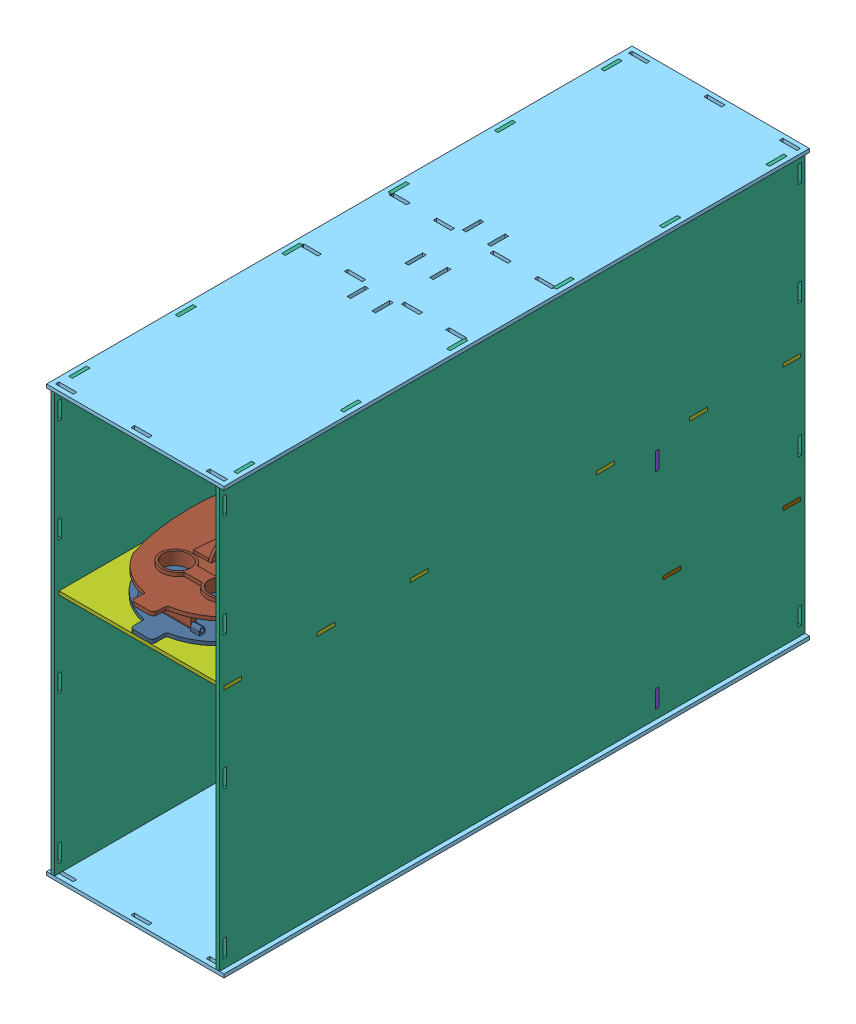
SolidWorks assembly respirador, configuration Default. Lengths in mm.
Overall size (200 480 670.69).
25 component instances, 12 part files, 76 mates.
Components (placement in the parent):
- frente de motor-1: frente de motor [Default] at (-8.8174 -77.0345 -7.3085) size (4 194 150)
- lateral de motor-1: lateral de motor [Default] at (23.3277 -39.5375 40.6915) x (0 0 1) z (-1 0 0) size (4 83.46 80)
- lateral de motor-2: lateral de motor [Default] at (23.3277 -39.5375 -59.3085) x (0 0 1) z (-1 0 0) size (4 83.46 80)
- nema 17-1: nema 17 [Default] at (37.1826 -36.4473 -7.3085) x (-1 0 0) z (0 0 -1) size (67 45 41)
- rueda-1: rueda [Default] at (0.1826 83.0527 -7.3085) x (1 0 0) z (0 0.015748 -0.999876) size (4 160 160)
- lateral de motor-3: lateral de motor [Default] at (-64.9624 -39.5375 44.6915) x (0 0 -1) z (1 0 0) size (4 83.46 80)
- frente de motor-2: frente de motor [Default] at (-32.8174 -77.0345 -7.3085) x (-1 0 0) z (0 0 -1) size (4 194 150)
- lateral de motor-4: lateral de motor [Default] at (-64.9624 -39.5375 -55.3085) x (0 0 -1) z (1 0 0) size (4 83.46 80)
- rueda-2: rueda [Default] at (-41.8174 83.0527 -7.3085) x (-1 0 0) z (0 -0.015748 0.999876) size (4 160 160)
- lateral-1: lateral [Default] at (-93.6666 165.2996 94.5076) x (0 0 -1) z (1 0 0) size (4 480 660) (hidden)
- nema 17-2: nema 17 [Default] at (-78.8174 -36.4473 -7.3085) size (67 45 41)
- piso 2-1: piso 2 [Default] at (-20.8174 -80.9473 -7.4488) x (0 0 1) z (-1 0 0) size (660 4 200)
- lateral-3: lateral [Default] at (-115.8174 159.0527 -79.1232) size (4 480 660)
- entrepiso-3: entrepiso [Default] at (-21.8174 195.0527 -214.9488) x (0 0 -1) z (1 0 0) size (235 4 190)
- entrepiso-4: entrepiso [Default] at (-19.8174 195.0527 200.0512) x (0 0 1) z (-1 0 0) size (235 4 190)
- soporte de entrepiso-2: soporte de entrepiso [Default] at (-20.8174 61.0527 -168.8431) x (-1 0 0) z (0 -1 0) size (190 4 276)
- piso para electronica-2: piso para electronica [Default] at (-20.8174 55.0527 -250.6481) x (0 0 -1) z (1 0 0) size (163.61 4 190)
- tapa de fuelle-1: tapa de fuelle [Default] at (-19.3174 199.0527 192.5512) x (0 0 1) z (-1 0 0) size (233.07 11.87 160.08)
- tapa de fuelle-2: tapa de fuelle [Default] at (-19.3174 199.0527 -207.4488) x (0 0 -1) z (1 0 0) size (233.07 11.87 160.08)
- tapa sup de fuelle-1: tapa sup de fuelle [Default] at (-19.3174 216.1024 192.16) x (0 0.076315 0.997084) z (-1 0 0) size (265 43.89 160.08)
- tapa sup de fuelle-2: tapa sup de fuelle [Default] at (-19.3174 265.1289 -227.2976) x (0 -0.487579 -0.873079) z (1 0 0) size (265 43.89 160.08)
- bastago-1: bastago [Default] at (-24.3174 248.4225 -61.1893) x (1 0 0) z (0 0.534387 0.84524) size (38 235 15)
- bastago-2: bastago [Default] at (-16.3174 118.2477 24.0857) x (-1 0 0) z (0 0.333942 -0.942594) size (38 235 15)
- lateral-4: lateral [Default] at (70.1826 159.0527 -79.1232) size (4 480 660)
- piso 2-2: piso 2 [Default] at (-20.8174 395.0527 -7.4488) x (0 0 1) z (-1 0 0) size (660 4 200)
Mates (geometry in assembly coordinates):
- Parallel1: parallel: plane of frente de motor-1 through (-4.8174 -77.0345 -7.3085) normal (1 0 0); plane of lateral de motor-1 through (-4.8174 -25.4846 44.6915) normal (-1 0 0)
- Coincident1: coincident: plane of frente de motor-1 through (-4.8174 -5.4846 44.6915) normal (0 0 -1); plane of lateral de motor-1 through (23.3277 -39.5375 44.6915) normal (0 0 1)
- Coincident2: coincident: plane of frente de motor-1 through (-4.8174 -5.4846 44.6915) normal (0 -1 0); plane of lateral de motor-1 through (-8.8174 -5.4846 44.6915) normal (0 1 0)
- Coincident3: coincident: plane of frente de motor-1 through (-4.8174 -77.0345 -7.3085) normal (1 0 0); plane of lateral de motor-1 through (-4.8174 -25.4846 44.6915) normal (-1 0 0)
- Parallel2: parallel: plane of frente de motor-1 through (-4.8174 -77.0345 -7.3085) normal (1 0 0); plane of lateral de motor-2 through (-4.8174 -25.4846 -55.3085) normal (-1 0 0)
- Coincident4: coincident: plane of frente de motor-1 through (-4.8174 -5.4846 -59.3085) normal (0 -1 0); plane of lateral de motor-2 through (-8.8174 -5.4846 -55.3085) normal (0 1 0)
- Coincident5: coincident: plane of frente de motor-1 through (-4.8174 -25.4846 -59.3085) normal (0 0 1); plane of lateral de motor-2 through (23.3277 -39.5375 -59.3085) normal (0 0 -1)
- Coincident6: coincident: plane of frente de motor-1 through (-4.8174 -77.0345 -7.3085) normal (1 0 0); plane of lateral de motor-2 through (-4.8174 -25.4846 -55.3085) normal (-1 0 0)
- Concentric1: concentric: cylinder of frente de motor-1 through (-4.8174 -36.4473 -7.3085) axis (-1 0 0) radius 11; cylinder of nema 17-1 through (-7.8174 -36.4473 -7.3085) axis (1 0 0) radius 11
- Concentric2: concentric: cylinder of frente de motor-1 through (-4.8174 -20.5374 8.6014) axis (-1 0 0) radius 1.75; cylinder of nema 17-1 through (-0.8174 -20.5374 8.6014) axis (-1 0 0) radius 1.5
- Coincident7: coincident: plane of frente de motor-1 through (-4.8174 -77.0345 -7.3085) normal (1 0 0); plane of nema 17-1 through (-4.8174 -36.4473 -7.3085) normal (-1 0 0)
- Concentric3: concentric: cylinder of frente de motor-1 through (-4.8174 83.0527 -7.3085) axis (-1 0 0) radius 10; cylinder of rueda-1 through (4.1826 83.0527 -7.3085) axis (-1 0 0) radius 3
- Distance1: distance = 5 mm: plane of rueda-1 through (0.1826 83.0527 -7.3085) normal (-1 0 0); plane of frente de motor-1 through (-4.8174 -77.0345 -7.3085) normal (1 0 0)
- Parallel3: parallel: plane of ? through (-351.9923 -70.7004 99.5076) normal (0 0 1); plane of lateral-1 through (-93.6666 165.2996 90.5076) normal (0 0 -1)
- Coincident11: coincident: plane of ? through (-211.9923 -70.7004 94.5076) normal (0 0 -1); plane of lateral-1 through (-93.6666 165.2996 94.5076) normal (0 0 1)
- Coincident12: coincident: plane of ? through (-331.9923 -70.7004 94.5076) normal (1 0 0); plane of lateral-1 through (-331.9923 -74.7004 90.5076) normal (-1 0 0)
- Coincident13: coincident: plane of ? through (-21.9923 -70.7004 -0.4924) normal (0 1 0); plane of lateral-1 through (148.0077 -70.7004 90.5076) normal (0 -1 0)
- Concentric4: concentric: cylinder of frente de motor-2 through (-36.8174 -36.4473 -7.3085) axis (1 0 0) radius 11; cylinder of nema 17-2 through (-75.8174 -36.4473 -7.3085) axis (-1 0 0) radius 5
- Concentric5: concentric: cylinder of frente de motor-2 through (-36.8174 -20.5374 -23.2184) axis (1 0 0) radius 1.75; cylinder of nema 17-2 through (-40.8174 -20.5374 -23.2184) axis (1 0 0) radius 1.5
- Coincident14: coincident: plane of frente de motor-2 through (-36.8174 -77.0345 -7.3085) normal (-1 0 0); plane of nema 17-2 through (-36.8174 -36.4473 -7.3085) normal (1 0 0)
- Parallel4: parallel: plane of lateral-1 through (-93.6666 165.2996 90.5076) normal (0 0 -1); plane of ? through (-93.6666 165.2996 -91.4924) normal (0 0 1)
- Coincident15: coincident: plane of ? through (-331.9923 -70.7004 -91.4924) normal (0 0 -1); plane of ? through (-93.6666 165.2996 -91.4924) normal (0 0 1)
- Coincident16: coincident: plane of ? through (-21.9923 -70.7004 -0.4924) normal (0 1 0); plane of ? through (-211.9923 -70.7004 -95.4924) normal (0 -1 0)
- Coincident17: coincident: plane of ? through (-331.9923 -70.7004 -95.4924) normal (1 0 0); plane of ? through (-331.9923 -74.7004 -95.4924) normal (-1 0 0)
- Parallel5: parallel: plane of ? through (-21.9923 -70.7004 -0.4924) normal (0 1 0); plane of ? through (-229.4923 201.2996 -1.4924) normal (0 -1 0)
- Parallel6: parallel: plane of lateral-1 through (-93.6666 165.2996 90.5076) normal (0 0 -1); plane of ? through (-241.9923 201.2996 90.5076) normal (0 0 1)
- Coincident18: coincident: plane of ? through (-346.9923 205.2996 -95.4924) normal (0 -1 0); plane of ? through (-229.4923 205.2996 -1.4924) normal (0 1 0)
- Coincident19: coincident: plane of lateral-1 through (-346.9923 205.2996 90.5076) normal (1 0 0); plane of ? through (-346.9923 201.2996 -95.4924) normal (-1 0 0)
- Coincident20: coincident: plane of lateral-1 through (-93.6666 165.2996 90.5076) normal (0 0 -1); plane of ? through (-241.9923 201.2996 90.5076) normal (0 0 1)
- Coincident21: coincident: plane of ? through (-229.4923 205.2996 -1.4924) normal (0 1 0); plane of ? through (-183.3866 205.2996 49.5076) normal (0 1 0)
- Coincident22: coincident: plane of ? through (-187.3866 171.2996 -95.4924) normal (1 0 0); plane of ? through (-187.3866 67.2996 -0.4924) normal (-1 0 0)
- Coincident25: coincident: plane of ? through (-93.6666 165.2996 -91.4924) normal (0 0 1); plane of ? through (-183.3866 191.2996 -91.4924) normal (0 0 -1)
- Coincident26: coincident: plane of ? through (-183.3866 65.2996 49.5076) normal (0 -1 0); plane of ? through (-265.1916 65.2996 -0.4924) normal (0 1 0)
- Coincident27: coincident: plane of ? through (-183.3866 67.2996 -0.4924) normal (1 0 0); plane of ? through (-183.3866 65.2996 -50.4924) normal (1 0 0)
- Coincident28: coincident: plane of ? through (-93.6666 165.2996 -91.4924) normal (0 0 1); plane of ? through (-211.9923 65.2996 -91.4924) normal (0 0 -1)
- Parallel9: parallel: plane of ? through (303.0077 205.2996 -95.4924) normal (-1 0 0); plane of ? through (305.3575 201.2996 94.5076) normal (1 0 0)
- Coincident36: coincident: plane of lateral de motor-4 through (-64.9624 -39.5375 -59.3085) normal (0 0 -1); plane of piso 2-1 through (-111.8174 -76.9473 -59.3085) normal (0 0 1)
- Coincident37: coincident: plane of lateral de motor-4 through (-62.8174 -76.9473 -59.3085) normal (0 -1 0); plane of piso 2-1 through (-20.8174 -76.9473 -7.4488) normal (0 1 0)
- Coincident38: coincident: plane of frente de motor-2 through (-32.8174 -77.0345 -7.3085) normal (1 0 0); plane of piso 2-1 through (-32.8174 -76.9473 -82.3085) normal (-1 0 0)
- Coincident39: coincident: plane of piso 2-1 through (-111.8174 -76.9473 302.5512) normal (-1 0 0); plane of lateral-3 through (-111.8174 159.0527 -79.1232) normal (1 0 0)
- Coincident40: coincident: plane of piso 2-1 through (-115.8174 -76.9473 282.5512) normal (0 0 1); plane of lateral-3 through (-111.8174 -76.9473 282.5512) normal (0 0 -1)
- Coincident41: coincident: plane of piso 2-1 through (-20.8174 -76.9473 -7.4488) normal (0 1 0); plane of lateral-3 through (-111.8174 -76.9473 322.5512) normal (0 -1 0)
- Coincident42: coincident: plane of lateral-3 through (-111.8174 159.0527 -79.1232) normal (1 0 0); plane of entrepiso-3 through (-111.8174 199.0527 -227.4488) normal (-1 0 0)
- Coincident43: coincident: plane of lateral-3 through (-111.8174 199.0527 -332.4488) normal (0 0 1); plane of entrepiso-3 through (-115.8174 199.0527 -332.4488) normal (0 0 -1)
- Coincident44: coincident: plane of lateral-3 through (-111.8174 199.0527 -332.4488) normal (0 -1 0); plane of entrepiso-3 through (-21.8174 199.0527 -214.9488) normal (0 1 0)
- Coincident45: coincident: plane of lateral-3 through (-111.8174 159.0527 -79.1232) normal (1 0 0); plane of entrepiso-4 through (-111.8174 199.0527 107.5512) normal (-1 0 0)
- Coincident46: coincident: plane of lateral-3 through (-111.8174 199.0527 107.5512) normal (0 -1 0); plane of entrepiso-4 through (-19.8174 199.0527 200.0512) normal (0 1 0)
- Coincident48: coincident: plane of lateral-3 through (-111.8174 199.0527 87.5512) normal (0 0 1); plane of entrepiso-4 through (-111.8174 199.0527 87.5512) normal (0 0 -1)
- Coincident55: coincident: plane of entrepiso-3 through (-21.8174 199.0527 -214.9488) normal (0 1 0); plane of soporte de entrepiso-2 through (29.1826 199.0527 -172.8431) normal (0 1 0)
- Coincident56: coincident: plane of lateral-3 through (-111.8174 165.0527 -172.8431) normal (0 0 1); plane of soporte de entrepiso-2 through (-20.8174 61.0527 -172.8431) normal (0 0 -1)
- Coincident57: coincident: plane of lateral-3 through (-111.8174 159.0527 -79.1232) normal (1 0 0); plane of soporte de entrepiso-2 through (-111.8174 -46.9473 -172.8431) normal (-1 0 0)
- Coincident58: coincident: plane of soporte de entrepiso-2 through (-20.8174 61.0527 -168.8431) normal (0 0 1); plane of piso para electronica-2 through (29.1826 59.0527 -168.8431) normal (0 0 1)
- Coincident59: coincident: plane of lateral-3 through (-111.8174 59.0527 -312.4488) normal (0 -1 0); plane of piso para electronica-2 through (-20.8174 59.0527 -250.6481) normal (0 1 0)
- Coincident60: coincident: plane of lateral-3 through (-111.8174 159.0527 -79.1232) normal (1 0 0); plane of piso para electronica-2 through (-111.8174 59.0527 -197.4488) normal (-1 0 0)
- Coincident61: coincident: plane of entrepiso-4 through (-19.8174 199.0527 200.0512) normal (0 1 0); plane of tapa de fuelle-1 through (-203.6819 199.0527 170.9372) normal (0 -1 0)
- Coincident62: coincident: plane of tapa de fuelle-1 through (-10.8174 203.0527 317.5512) normal (0 0 1); plane of entrepiso-4 through (74.1826 199.0527 317.5512) normal (0 0 1)
- Distance6: distance = 80 mm: plane of tapa de fuelle-1 through (-31.8174 203.0527 313.5512) normal (-1 0 0); plane of lateral-3 through (-111.8174 159.0527 -79.1232) normal (1 0 0)
- Coincident63: coincident: plane of entrepiso-3 through (-21.8174 199.0527 -214.9488) normal (0 1 0); plane of tapa de fuelle-2 through (165.0472 199.0527 -185.8348) normal (0 -1 0)
- Coincident64: coincident: plane of entrepiso-3 through (-115.8174 199.0527 -332.4488) normal (0 0 -1); plane of tapa de fuelle-2 through (-27.8174 203.0527 -332.4488) normal (0 0 -1)
- Distance7: distance = 80 mm: plane of tapa de fuelle-2 through (-31.8174 203.0527 -318.1066) normal (-1 0 0); plane of lateral-3 through (-111.8174 159.0527 -79.1232) normal (1 0 0)
- Concentric6: concentric: cylinder of tapa de fuelle-1 through (-74.3174 207.0527 283.5785) axis (1 0 0) radius 2; cylinder of tapa sup de fuelle-1 through (14.6826 207.0527 283.5785) axis (-1 0 0) radius 2
- Coincident65: coincident: plane of tapa de fuelle-1 through (-44.3174 211.0527 280.5785) normal (1 0 0); plane of tapa sup de fuelle-1 through (-44.3174 205.0508 278.9968) normal (-1 0 0)
- Concentric7: concentric: cylinder of tapa de fuelle-2 through (35.6826 207.0527 -298.4762) axis (-1 0 0) radius 2; cylinder of tapa sup de fuelle-2 through (-53.3174 207.0527 -298.4762) axis (1 0 0) radius 2
- Coincident66: coincident: plane of tapa de fuelle-2 through (5.6826 211.0527 -295.4762) normal (-1 0 0); plane of tapa sup de fuelle-2 through (5.6826 202.8435 -295.7775) normal (1 0 0)
- Concentric8: concentric: cylinder of tapa sup de fuelle-2 through (-54.3174 221.0878 -79.9998) axis (1 0 0) radius 2; cylinder of bastago-1 through (-16.3174 221.0878 -79.9998) axis (-1 0 0) radius 3.8245
- Concentric11: concentric: cylinder of tapa sup de fuelle-1 through (15.6826 340.0484 109.679) axis (-1 0 0) radius 2; cylinder of bastago-2 through (-24.3174 340.0484 109.679) axis (1 0 0) radius 3.8245
- Distance8: distance = 5 mm: plane of bastago-1 through (-24.3174 338.9941 -123.7754) normal (-1 0 0); plane of tapa sup de fuelle-2 through (-29.3174 268.0554 -271.3107) normal (1 0 0)
- Concentric12: concentric: cylinder of rueda-1 through (4.1826 13.0613 -8.4109) axis (-1 0 0) radius 2; cylinder of bastago-1 through (13.6826 13.0613 -8.4109) axis (-1 0 0) radius 3.8245
- Concentric13: concentric: cylinder of rueda-1 through (4.1826 153.044 -6.2061) axis (-1 0 0) radius 2; cylinder of bastago-2 through (-54.3174 153.044 -6.2061) axis (1 0 0) radius 3.8245
- Distance9: distance = 5 mm: plane of bastago-2 through (-24.3174 220.4303 65.061) normal (-1 0 0); plane of tapa sup de fuelle-1 through (-29.3174 242.8709 227.2194) normal (1 0 0)
- Coincident68: coincident: plane of entrepiso-4 through (70.1826 199.0527 212.5512) normal (1 0 0); plane of lateral-4 through (70.1826 159.0527 -79.1232) normal (-1 0 0)
- Coincident69: coincident: plane of entrepiso-4 through (-19.8174 195.0527 200.0512) normal (0 -1 0); plane of lateral-4 through (74.1826 195.0527 317.5512) normal (0 1 0)
- Coincident70: coincident: plane of piso 2-1 through (74.1826 -76.9473 282.5512) normal (0 0 1); plane of lateral-4 through (74.1826 -76.9473 282.5512) normal (0 0 -1)
- Coincident72: coincident: plane of lateral-3 through (-111.8174 399.0527 302.5512) normal (0 1 0); plane of piso 2-2 through (-20.8174 399.0527 -7.4488) normal (0 1 0)
- Coincident73: coincident: plane of lateral-3 through (-111.8174 395.0527 -297.4488) normal (0 0 1); plane of piso 2-2 through (-115.8174 399.0527 -297.4488) normal (0 0 -1)
- Coincident75: coincident: plane of lateral-3 through (-111.8174 159.0527 -79.1232) normal (1 0 0); plane of piso 2-2 through (-111.8174 399.0527 -317.4488) normal (-1 0 0)
